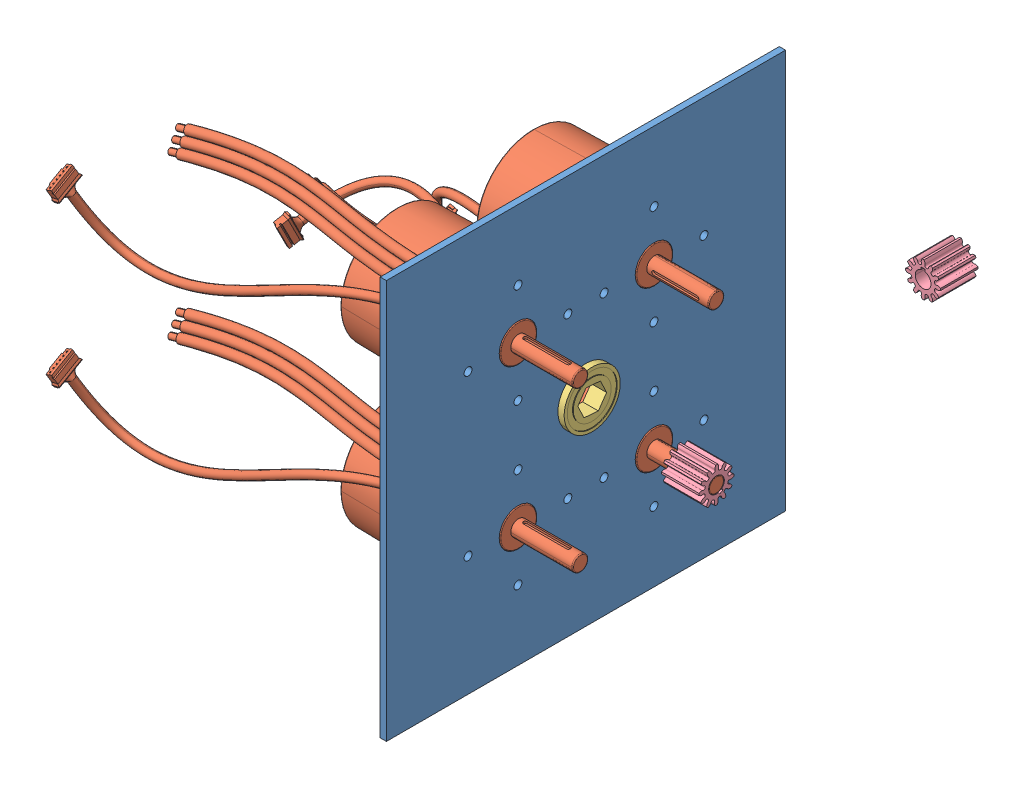
SolidWorks assembly Gearbox, configuration Default. Lengths in mm.
Overall size (216.08 203.2 259.95).
10 component instances, 4 part files, 17 mates.
Components (placement in the parent):
- GearboxPlate-1: GearboxPlate [Default] at (73.1611 96.5551 164.674) size (3.17 203.2 203.2)
- Neo-1: Neo [Default] at (69.9861 137.2321 130.0521) x (0 1 0) z (1 0 0) size (98.87 73.45 204.78)
- Neo-2: Neo [Default] at (69.9861 137.2321 199.2959) x (0 0 -1) z (1 0 0) size (98.87 73.45 204.78)
- Neo-3: Neo [Default] at (69.9861 55.8781 130.0521) x (0 0 1) z (1 0 0) size (98.87 73.45 204.78)
- Neo-4: Neo [Default] at (69.9861 55.8781 199.2959) x (0 0 -1) z (1 0 0) size (98.87 73.45 204.78)
- 0_500_Hex_ID_x_1_125_OD_x_0_313_WD_Flanged_Bearing_v2_217-3875.step-1: 0_500_Hex_ID_x_1_125_OD_x_0_313_WD_Flanged_Bearing_v2_217-3875.step [Default] at (76.3361 96.5551 164.674) x (0 -0.905326 -0.424718) z (0 0.424718 -0.905326) size (31.12 7.94 31.12)
- 12t steel.step-1: 12t steel.step [Default] at (107.396 96.2583 17.7507) size (17.78 17.78 19.05)
- 12t steel.step-2: 12t steel.step [Default] at (107.396 96.2583 17.7507) size (17.78 17.78 19.05)
- 12t steel.step-3: 12t steel.step [Default] at (95.4611 55.8781 130.0521) x (0 0.484123 -0.875) z (-1 0 0) size (17.78 17.78 19.05)
- 12t steel.step-4: 12t steel.step [Default] at (107.396 96.2583 17.7507) size (17.78 17.78 19.05)
Mates (geometry in assembly coordinates):
- Concentric1: concentric anti-aligned: circle of GearboxPlate-1; circle of Neo-1
- Coincident1: coincident anti-aligned: plane of GearboxPlate-1 through (69.9861 96.5551 164.674) normal (-1 0 0); plane of Neo-1 through (69.9861 137.2321 130.0521) normal (1 0 0)
- Concentric3: concentric anti-aligned: circle of GearboxPlate-1; circle of Neo-3
- Coincident3: coincident anti-aligned: plane of GearboxPlate-1 through (69.9861 96.5551 164.674) normal (-1 0 0); plane of Neo-3 through (69.9861 55.8781 130.0521) normal (1 0 0)
- Concentric4: concentric anti-aligned: circle of GearboxPlate-1; circle of Neo-2
- Coincident4: coincident anti-aligned: plane of GearboxPlate-1 through (69.9861 96.5551 164.674) normal (-1 0 0); plane of Neo-2 through (69.9861 137.2321 199.2959) normal (1 0 0)
- Concentric5: concentric anti-aligned: circle of GearboxPlate-1; circle of Neo-4
- Coincident5: coincident anti-aligned: plane of GearboxPlate-1 through (69.9861 96.5551 164.674) normal (-1 0 0); plane of Neo-4 through (69.9861 55.8781 199.2959) normal (1 0 0)
- Concentric6: concentric anti-aligned: cylinder of GearboxPlate-1 through (69.9861 96.5551 164.674) axis (1 0 0) radius 14.2621; cylinder of 0_500_Hex_ID_x_1_125_OD_x_0_313_WD_Flanged_Bearing_v2_217-3875.step-1 through (76.3361 96.5551 164.674) axis (-1 0 0) radius 14.2748
- Coincident6: coincident anti-aligned: plane of GearboxPlate-1 through (69.9861 96.5551 164.674) normal (-1 0 0); plane of 0_500_Hex_ID_x_1_125_OD_x_0_313_WD_Flanged_Bearing_v2_217-3875.step-1 through (69.9861 82.4705 158.0664) normal (1 0 0)
- Concentric7: concentric aligned: circle of GearboxPlate-1; circle of Neo-2
- Concentric8: concentric aligned: circle of GearboxPlate-1; circle of Neo-3
- Concentric9: concentric aligned: circle of GearboxPlate-1; circle of Neo-1
- Concentric10: concentric aligned: circle of GearboxPlate-1; circle of Neo-4
- Concentric12: concentric: circle of Neo-3; circle of 12t steel.step-3
- Coincident12: coincident: plane of Neo-3 through (104.9861 55.8781 130.0521) normal (1 0 0); plane of 12t steel.step-3 through (104.9861 55.8781 130.0521) normal (1 0 0)
- Coincident13: coincident aligned: line of Neo-3 through (98.9861 52.0052 129.0521) axis (-1 0 0); line of 12t steel.step-3 through (104.9861 52.0052 129.0521) axis (-1 0 0)
